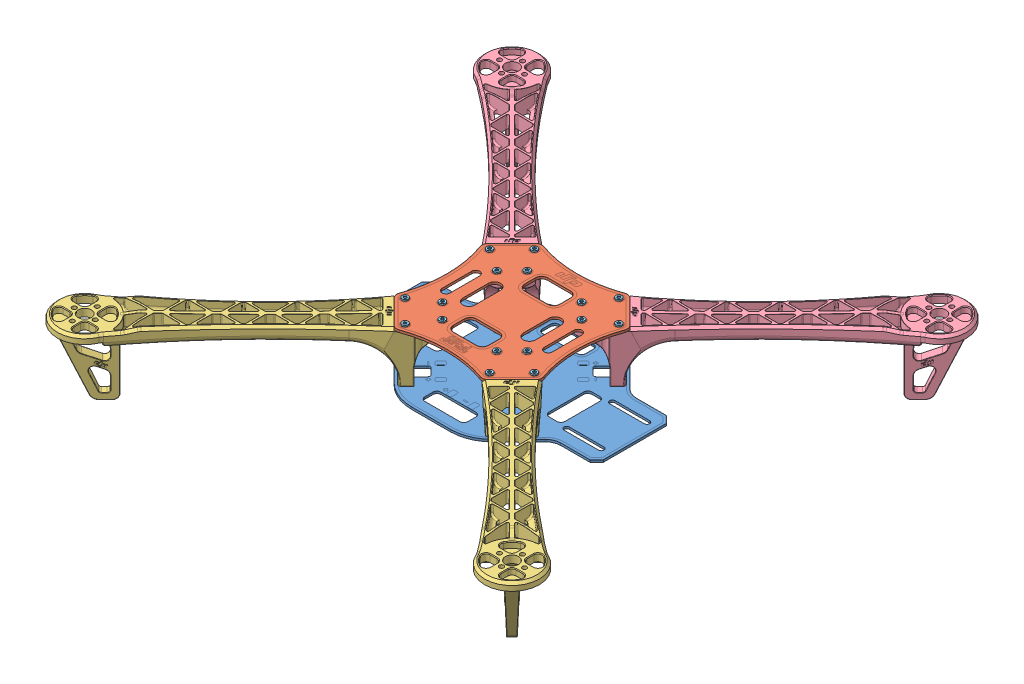
SolidWorks assembly FlameWheel_F450, configuration Default. Lengths in mm.
Overall size (375.45 55.91 375.45).
30 component instances, 5 part files, 134 mates.
Components (placement in the parent):
- FlameWheel_F450_Base_Bottom-1: FlameWheel_F450_Base_Bottom [Default] at (0 -19.2036 0) x (-1 0 0) z (0 0 -1) size (182 1.6 118)
- FlameWheel_F450_Base_Top-1: FlameWheel_F450_Base_Top [Default] at (0 19.2286 0) x (-1 0 0) z (0 0 -1) size (108.15 1.65 108.15)
- FlameWheel_F450_Arm_White-1: FlameWheel_F450_Arm_White [Default] at (98.3674 20.1974 98.378) x (-0.707107 0 0.707107) z (-0.707107 0 -0.707107) size (40.75 55.34 213.92)
- FlameWheel_F450_Arm_White-2: FlameWheel_F450_Arm_White [Default] at (-98.378 20.1974 98.3674) x (-0.707107 0 -0.707107) z (0.707107 0 -0.707107) size (40.75 55.34 213.92)
- FlameWheel_F450_Arm_Red-1: FlameWheel_F450_Arm_Red [Default] at (-98.3674 20.1974 -98.378) x (0.707107 0 -0.707107) z (0.707107 0 0.707107) size (40.75 55.34 213.92)
- FlameWheel_F450_Arm_Red-2: FlameWheel_F450_Arm_Red [Default] at (98.378 20.1974 -98.3674) x (0.707107 0 0.707107) z (-0.707107 0 0.707107) size (40.75 55.34 213.92)
- FlameWheel_F450_Base_Screw-1: FlameWheel_F450_Base_Screw [Default] at (31.5406 20.0546 -20.2253) x (-0.297035 0 0.954867) z (-0.954867 0 -0.297035) size (4.5 7.42 4.5)
- FlameWheel_F450_Base_Screw-2: FlameWheel_F450_Base_Screw [Default] at (20.2269 20.0546 -31.539) x (-0.291663 0 0.956521) z (-0.956521 0 -0.291663) size (4.5 7.42 4.5)
- FlameWheel_F450_Base_Screw-3: FlameWheel_F450_Base_Screw [Default] at (48.0835 20.0546 -31.465) x (-0.305735 0 0.952117) z (-0.952117 0 -0.305735) size (4.5 7.42 4.5)
- FlameWheel_F450_Base_Screw-4: FlameWheel_F450_Base_Screw [Default] at (31.4665 20.0546 -48.082) x (-0.301237 0 0.953549) z (-0.953549 0 -0.301237) size (4.5 7.42 4.5)
- FlameWheel_F450_Base_Screw-5: FlameWheel_F450_Base_Screw [Default] at (48.082 20.0546 31.4665) x (-0.954122 0 -0.299419) z (0.299419 0 -0.954122) size (4.5 7.42 4.5)
- FlameWheel_F450_Base_Screw-6: FlameWheel_F450_Base_Screw [Default] at (31.539 20.0546 20.2269) x (-0.957492 0 -0.28846) z (0.28846 0 -0.957492) size (4.5 7.42 4.5)
- FlameWheel_F450_Base_Screw-7: FlameWheel_F450_Base_Screw [Default] at (20.2253 20.0546 31.5406) x (-0.955334 0 -0.295529) z (0.295529 0 -0.955334) size (4.5 7.42 4.5)
- FlameWheel_F450_Base_Screw-8: FlameWheel_F450_Base_Screw [Default] at (31.465 20.0546 48.0835) x (-0.955194 0 -0.29598) z (0.29598 0 -0.955194) size (4.5 7.42 4.5)
- FlameWheel_F450_Base_Screw-9: FlameWheel_F450_Base_Screw [Default] at (-48.0836 20.0546 31.465) x (0.293117 0 -0.956076) z (0.956076 0 0.293117) size (4.5 7.42 4.5)
- FlameWheel_F450_Base_Screw-10: FlameWheel_F450_Base_Screw [Default] at (-31.4665 20.0546 48.082) x (0.288843 0 -0.957376) z (0.957376 0 0.288843) size (4.5 7.42 4.5)
- FlameWheel_F450_Base_Screw-11: FlameWheel_F450_Base_Screw [Default] at (-20.2269 20.0546 31.539) x (0.306596 0 -0.95184) z (0.95184 0 0.306596) size (4.5 7.42 4.5)
- FlameWheel_F450_Base_Screw-12: FlameWheel_F450_Base_Screw [Default] at (-31.5406 20.0546 20.2253) x (0.301712 0 -0.953399) z (0.953399 0 0.301712) size (4.5 7.42 4.5)
- FlameWheel_F450_Base_Screw-13: FlameWheel_F450_Base_Screw [Default] at (-31.539 20.0546 -20.2269) x (0.953252 0 0.302177) z (-0.302177 0 0.953252) size (4.5 7.42 4.5)
- FlameWheel_F450_Base_Screw-14: FlameWheel_F450_Base_Screw [Default] at (-20.2253 20.0546 -31.5406) x (0.958789 0 0.284118) z (-0.284118 0 0.958789) size (4.5 7.42 4.5)
- FlameWheel_F450_Base_Screw-15: FlameWheel_F450_Base_Screw [Default] at (-31.465 20.0546 -48.0835) x (0.952775 0 0.303679) z (-0.303679 0 0.952775) size (4.5 7.42 4.5)
- FlameWheel_F450_Base_Screw-16: FlameWheel_F450_Base_Screw [Default] at (-48.082 20.0546 -31.4665) x (0.951324 0 0.308194) z (-0.308194 0 0.951324) size (4.5 7.42 4.5)
- FlameWheel_F450_Base_Screw-17: FlameWheel_F450_Base_Screw [Default] at (-32.0325 -20.0046 46.5265) x (-0.841902 0 -0.53963) z (-0.53963 0 0.841902) size (4.5 7.42 4.5)
- FlameWheel_F450_Base_Screw-18: FlameWheel_F450_Base_Screw [Default] at (-46.5282 -20.0046 32.0308) x (-0.845928 0 -0.533297) z (-0.533297 0 0.845928) size (4.5 7.42 4.5)
- FlameWheel_F450_Base_Screw-19: FlameWheel_F450_Base_Screw [Default] at (-46.5265 -20.0046 -32.0325) x (0.545636 0 -0.838023) z (-0.838023 0 -0.545636) size (4.5 7.42 4.5)
- FlameWheel_F450_Base_Screw-20: FlameWheel_F450_Base_Screw [Default] at (32.0325 -20.0046 -46.5265) x (0.846067 0 0.533077) z (0.533077 0 -0.846067) size (4.5 7.42 4.5)
- FlameWheel_F450_Base_Screw-21: FlameWheel_F450_Base_Screw [Default] at (46.5265 -20.0046 32.0325) x (-0.547323 0 0.836921) z (0.836921 0 0.547323) size (4.5 7.42 4.5)
- FlameWheel_F450_Base_Screw-22: FlameWheel_F450_Base_Screw [Default] at (46.5282 -20.0046 -32.0308) x (0.847468 0 0.530847) z (0.530847 0 -0.847468) size (4.5 7.42 4.5)
- FlameWheel_F450_Base_Screw-23: FlameWheel_F450_Base_Screw [Default] at (-32.0308 -20.0046 -46.5282) x (0.54048 0 -0.841357) z (-0.841357 0 -0.54048) size (4.5 7.42 4.5)
- FlameWheel_F450_Base_Screw-24: FlameWheel_F450_Base_Screw [Default] at (32.0308 -20.0046 46.5282) x (-0.540245 0 0.841508) z (0.841508 0 0.540245) size (4.5 7.42 4.5)
Mates (geometry in assembly coordinates):
- Coincident1: coincident aligned: plane of FlameWheel_F450_Base_Bottom-1 through (36.6281 20.0036 51.1238) normal (0.707107 0 0.707107); plane of FlameWheel_F450_Base_Top-1 through (35.0464 -18.4036 52.7056) normal (0.707107 0 0.707107)
- Coincident2: coincident aligned: plane of FlameWheel_F450_Base_Bottom-1 through (-56.4271 20.0036 31.3248) normal (-0.707107 0 0.707107); plane of FlameWheel_F450_Base_Top-1 through (-52.7056 -18.4036 35.0464) normal (-0.707107 0 0.707107)
- Coincident3: coincident aligned: plane of FlameWheel_F450_Base_Bottom-1 through (-32.25 20.0036 -55.502) normal (-0.707107 0 -0.707107); plane of FlameWheel_F450_Base_Top-1 through (-52.7056 -18.4036 -35.0464) normal (-0.707107 0 -0.707107)
- Coincident4: coincident aligned: plane of FlameWheel_F450_Base_Bottom-1 through (32.25 20.0036 -55.502) normal (0.707107 0 -0.707107); plane of FlameWheel_F450_Base_Top-1 through (35.0464 -18.4036 -52.7056) normal (0.707107 0 -0.707107)
- Coincident12: coincident anti-aligned: plane of FlameWheel_F450_Base_Top-1 through (0 -18.4026 0) normal (0 1 0); plane of FlameWheel_F450_Arm_Red-2 through (-31.3302 -18.4026 -53.6641) normal (0 -1 0)
- Coincident13: coincident anti-aligned: plane of FlameWheel_F450_Base_Top-1 through (0 -18.4026 0) normal (0 1 0); plane of FlameWheel_F450_Arm_Red-1 through (53.6641 -18.4026 -31.3302) normal (0 -1 0)
- Coincident14: coincident anti-aligned: plane of FlameWheel_F450_Base_Top-1 through (0 -18.4026 0) normal (0 1 0); plane of FlameWheel_F450_Arm_White-2 through (31.3302 -18.4026 53.6641) normal (0 -1 0)
- Coincident15: coincident anti-aligned: plane of FlameWheel_F450_Base_Top-1 through (0 -18.4026 0) normal (0 1 0); plane of FlameWheel_F450_Arm_White-1 through (-53.6641 -18.4026 31.3302) normal (0 -1 0)
- Concentric10: concentric aligned: circle of FlameWheel_F450_Base_Top-1; circle of FlameWheel_F450_Arm_Red-2
- Concentric11: concentric aligned: circle of FlameWheel_F450_Base_Top-1; circle of FlameWheel_F450_Arm_Red-2
- Concentric12: concentric aligned: circle of FlameWheel_F450_Base_Top-1; circle of FlameWheel_F450_Arm_Red-2
- Concentric13: concentric aligned: circle of FlameWheel_F450_Base_Top-1; circle of FlameWheel_F450_Arm_Red-2
- Concentric14: concentric aligned: circle of FlameWheel_F450_Base_Top-1; circle of FlameWheel_F450_Arm_Red-1
- Concentric15: concentric aligned: circle of FlameWheel_F450_Base_Top-1; circle of FlameWheel_F450_Arm_Red-1
- Concentric16: concentric aligned: circle of FlameWheel_F450_Base_Top-1; circle of FlameWheel_F450_Arm_Red-1
- Concentric17: concentric aligned: circle of FlameWheel_F450_Base_Top-1; circle of FlameWheel_F450_Arm_Red-1
- Concentric18: concentric aligned: circle of FlameWheel_F450_Base_Top-1; circle of FlameWheel_F450_Arm_White-2
- Concentric19: concentric aligned: circle of FlameWheel_F450_Base_Top-1; circle of FlameWheel_F450_Arm_White-2
- Concentric20: concentric aligned: circle of FlameWheel_F450_Base_Top-1; circle of FlameWheel_F450_Arm_White-2
- Concentric21: concentric aligned: circle of FlameWheel_F450_Base_Top-1; circle of FlameWheel_F450_Arm_White-2
- Concentric22: concentric aligned: circle of FlameWheel_F450_Base_Top-1; circle of FlameWheel_F450_Arm_White-1
- Concentric23: concentric aligned: circle of FlameWheel_F450_Base_Top-1; circle of FlameWheel_F450_Arm_White-1
- Concentric24: concentric aligned: circle of FlameWheel_F450_Base_Top-1; circle of FlameWheel_F450_Arm_White-1
- Concentric25: concentric aligned: circle of FlameWheel_F450_Base_Top-1; circle of FlameWheel_F450_Arm_White-1
- Concentric26: concentric anti-aligned: circle of FlameWheel_F450_Base_Bottom-1; circle of FlameWheel_F450_Arm_White-2
- Concentric27: concentric anti-aligned: circle of FlameWheel_F450_Base_Bottom-1; circle of FlameWheel_F450_Arm_White-2
- Concentric28: concentric anti-aligned: circle of FlameWheel_F450_Base_Bottom-1; circle of FlameWheel_F450_Arm_Red-1
- Concentric29: concentric anti-aligned: circle of FlameWheel_F450_Base_Bottom-1; circle of FlameWheel_F450_Arm_Red-1
- Concentric30: concentric anti-aligned: circle of FlameWheel_F450_Base_Bottom-1; circle of FlameWheel_F450_Arm_Red-2
- Concentric31: concentric anti-aligned: circle of FlameWheel_F450_Base_Bottom-1; circle of FlameWheel_F450_Arm_Red-2
- Concentric32: concentric anti-aligned: circle of FlameWheel_F450_Base_Bottom-1; circle of FlameWheel_F450_Arm_White-1
- Concentric33: concentric anti-aligned: circle of FlameWheel_F450_Base_Bottom-1; circle of FlameWheel_F450_Arm_White-1
- Coincident24: coincident anti-aligned: plane of FlameWheel_F450_Base_Bottom-1 through (0 18.4026 0) normal (0 -1 0); plane of FlameWheel_F450_Arm_White-1 through (-36.8349 18.4026 47.3108) normal (0 1 0)
- Coincident25: coincident anti-aligned: plane of FlameWheel_F450_Base_Bottom-1 through (0 18.4026 0) normal (0 -1 0); plane of FlameWheel_F450_Arm_White-1 through (-51.0813 18.4026 31.9315) normal (0 1 0)
- Coincident26: coincident anti-aligned: plane of FlameWheel_F450_Base_Bottom-1 through (0 18.4026 0) normal (0 -1 0); plane of FlameWheel_F450_Arm_White-2 through (31.9315 18.4026 51.0813) normal (0 1 0)
- Coincident27: coincident anti-aligned: plane of FlameWheel_F450_Base_Bottom-1 through (0 18.4026 0) normal (0 -1 0); plane of FlameWheel_F450_Arm_White-2 through (47.3108 18.4026 36.8349) normal (0 1 0)
- Coincident28: coincident anti-aligned: plane of FlameWheel_F450_Base_Bottom-1 through (0 18.4026 0) normal (0 -1 0); plane of FlameWheel_F450_Arm_Red-1 through (51.0813 18.4026 -31.9315) normal (0 1 0)
- Coincident29: coincident anti-aligned: plane of FlameWheel_F450_Base_Bottom-1 through (0 18.4026 0) normal (0 -1 0); plane of FlameWheel_F450_Arm_Red-1 through (36.8349 18.4026 -47.3108) normal (0 1 0)
- Coincident30: coincident anti-aligned: plane of FlameWheel_F450_Base_Bottom-1 through (0 18.4026 0) normal (0 -1 0); plane of FlameWheel_F450_Arm_Red-2 through (-31.9315 18.4026 -51.0813) normal (0 1 0)
- Coincident31: coincident anti-aligned: plane of FlameWheel_F450_Base_Bottom-1 through (0 18.4026 0) normal (0 -1 0); plane of FlameWheel_F450_Arm_Red-2 through (-47.3108 18.4026 -36.8349) normal (0 1 0)
- Coincident32: coincident: point of FlameWheel_F450_Arm_White-1; point of FlameWheel_F450_Arm_White-2
- Coincident33: coincident: point of FlameWheel_F450_Arm_White-1; point of FlameWheel_F450_Arm_Red-2
- Coincident34: coincident: point of FlameWheel_F450_Arm_White-2; point of FlameWheel_F450_Arm_Red-2
- Coincident35: coincident: point of FlameWheel_F450_Arm_Red-1; point of FlameWheel_F450_Arm_Red-2
- Coincident36: coincident: point of FlameWheel_F450_Arm_White-1; point of FlameWheel_F450_Arm_Red-1
- Coincident37: coincident: point of FlameWheel_F450_Arm_White-2; point of FlameWheel_F450_Arm_Red-1
- Coincident38: coincident: unknown of ?
- Coincident39: coincident: unknown of ?
- Coincident40: coincident: unknown of ?
- Coincident41: coincident: unknown of ?
- Coincident44: coincident anti-aligned: plane of FlameWheel_F450_Base_Bottom-1 through (0 20.0046 0) normal (0 1 0); plane of FlameWheel_F450_Base_Screw-24 through (-32.0308 20.0046 46.5282) normal (0 -1 0)
- Coincident45: coincident anti-aligned: plane of FlameWheel_F450_Base_Bottom-1 through (0 20.0046 0) normal (0 1 0); plane of FlameWheel_F450_Base_Screw-17 through (32.0325 20.0046 46.5265) normal (0 -1 0)
- Coincident46: coincident anti-aligned: plane of FlameWheel_F450_Base_Bottom-1 through (0 20.0046 0) normal (0 1 0); plane of FlameWheel_F450_Base_Screw-19 through (46.5265 20.0046 -32.0325) normal (0 -1 0)
- Coincident47: coincident anti-aligned: plane of FlameWheel_F450_Base_Bottom-1 through (0 20.0046 0) normal (0 1 0); plane of FlameWheel_F450_Base_Screw-23 through (32.0308 20.0046 -46.5282) normal (0 -1 0)
- Coincident48: coincident anti-aligned: plane of FlameWheel_F450_Base_Bottom-1 through (0 20.0046 0) normal (0 1 0); plane of FlameWheel_F450_Base_Screw-18 through (46.5282 20.0046 32.0308) normal (0 -1 0)
- Coincident49: coincident anti-aligned: plane of FlameWheel_F450_Base_Bottom-1 through (0 20.0046 0) normal (0 1 0); plane of FlameWheel_F450_Base_Screw-20 through (-32.0325 20.0046 -46.5265) normal (0 -1 0)
- Coincident50: coincident anti-aligned: plane of FlameWheel_F450_Base_Bottom-1 through (0 20.0046 0) normal (0 1 0); plane of FlameWheel_F450_Base_Screw-22 through (-46.5282 20.0046 -32.0308) normal (0 -1 0)
- Coincident51: coincident anti-aligned: plane of FlameWheel_F450_Base_Bottom-1 through (0 20.0046 0) normal (0 1 0); plane of FlameWheel_F450_Base_Screw-21 through (-46.5265 20.0046 32.0325) normal (0 -1 0)
- Coincident53: coincident anti-aligned: plane of FlameWheel_F450_Base_Top-1 through (0 -20.0546 0) normal (0 -1 0); plane of FlameWheel_F450_Base_Screw-5 through (-48.082 -20.0546 31.4665) normal (0 1 0)
- Coincident54: coincident anti-aligned: plane of FlameWheel_F450_Base_Top-1 through (0 -20.0546 0) normal (0 -1 0); plane of FlameWheel_F450_Base_Screw-8 through (-31.465 -20.0546 48.0835) normal (0 1 0)
- Coincident55: coincident anti-aligned: plane of FlameWheel_F450_Base_Top-1 through (0 -20.0546 0) normal (0 -1 0); plane of FlameWheel_F450_Base_Screw-6 through (-31.539 -20.0546 20.2269) normal (0 1 0)
- Coincident56: coincident anti-aligned: plane of FlameWheel_F450_Base_Top-1 through (0 -20.0546 0) normal (0 -1 0); plane of FlameWheel_F450_Base_Screw-7 through (-20.2253 -20.0546 31.5406) normal (0 1 0)
- Coincident57: coincident anti-aligned: plane of FlameWheel_F450_Base_Top-1 through (0 -20.0546 0) normal (0 -1 0); plane of FlameWheel_F450_Base_Screw-1 through (-31.5406 -20.0546 -20.2253) normal (0 1 0)
- Coincident59: coincident anti-aligned: plane of FlameWheel_F450_Base_Top-1 through (0 -20.0546 0) normal (0 -1 0); plane of FlameWheel_F450_Base_Screw-3 through (-48.0835 -20.0546 -31.465) normal (0 1 0)
- Coincident60: coincident anti-aligned: plane of FlameWheel_F450_Base_Top-1 through (0 -20.0546 0) normal (0 -1 0); plane of FlameWheel_F450_Base_Screw-4 through (-31.4665 -20.0546 -48.082) normal (0 1 0)
- Coincident61: coincident anti-aligned: plane of FlameWheel_F450_Base_Top-1 through (0 -20.0546 0) normal (0 -1 0); plane of FlameWheel_F450_Base_Screw-2 through (-20.2269 -20.0546 -31.539) normal (0 1 0)
- Coincident62: coincident anti-aligned: plane of FlameWheel_F450_Base_Top-1 through (0 -20.0546 0) normal (0 -1 0); plane of FlameWheel_F450_Base_Screw-10 through (31.4665 -20.0546 48.082) normal (0 1 0)
- Coincident63: coincident anti-aligned: plane of FlameWheel_F450_Base_Top-1 through (0 -20.0546 0) normal (0 -1 0); plane of FlameWheel_F450_Base_Screw-9 through (48.0836 -20.0546 31.465) normal (0 1 0)
- Coincident64: coincident anti-aligned: plane of FlameWheel_F450_Base_Top-1 through (0 -20.0546 0) normal (0 -1 0); plane of FlameWheel_F450_Base_Screw-13 through (31.539 -20.0546 -20.2269) normal (0 1 0)
- Coincident65: coincident anti-aligned: plane of FlameWheel_F450_Base_Top-1 through (0 -20.0546 0) normal (0 -1 0); plane of FlameWheel_F450_Base_Screw-14 through (20.2253 -20.0546 -31.5406) normal (0 1 0)
- Coincident66: coincident anti-aligned: plane of FlameWheel_F450_Base_Top-1 through (0 -20.0546 0) normal (0 -1 0); plane of FlameWheel_F450_Base_Screw-11 through (20.2269 -20.0546 31.539) normal (0 1 0)
- Coincident67: coincident anti-aligned: plane of FlameWheel_F450_Base_Top-1 through (0 -20.0546 0) normal (0 -1 0); plane of FlameWheel_F450_Base_Screw-12 through (31.5406 -20.0546 20.2253) normal (0 1 0)
- Coincident70: coincident anti-aligned: plane of FlameWheel_F450_Base_Top-1 through (0 -20.0546 0) normal (0 -1 0); plane of FlameWheel_F450_Base_Screw-15 through (31.465 -20.0546 -48.0835) normal (0 1 0)
- Coincident71: coincident anti-aligned: plane of FlameWheel_F450_Base_Top-1 through (0 -20.0546 0) normal (0 -1 0); plane of FlameWheel_F450_Base_Screw-16 through (48.082 -20.0546 -31.4665) normal (0 1 0)
- Coincident72: coincident aligned: line of FlameWheel_F450_Base_Top-1 through (-48.0833 -20.0546 31.4663) axis (0 1 0); line of FlameWheel_F450_Base_Screw-5 through (-48.0833 -20.0546 31.4663) axis (0 1 0)
- Coincident73: coincident aligned: line of FlameWheel_F450_Base_Top-1 through (-31.4663 -20.0546 48.0833) axis (0 1 0); line of FlameWheel_F450_Base_Screw-8 through (-31.4663 -20.0546 48.0833) axis (0 1 0)
- Coincident74: coincident anti-aligned: line of FlameWheel_F450_Base_Top-1 through (-31.5403 -18.4026 20.2266) axis (0 -1 0); line of FlameWheel_F450_Base_Screw-6 through (-31.5403 -20.0546 20.2266) axis (0 1 0)
- Coincident75: coincident aligned: line of FlameWheel_F450_Base_Top-1 through (-20.2266 -20.0546 31.5403) axis (0 1 0); line of FlameWheel_F450_Base_Screw-7 through (-20.2266 -20.0546 31.5403) axis (0 1 0)
- Coincident76: coincident aligned: line of FlameWheel_F450_Base_Top-1 through (-48.0833 -20.0546 -31.4663) axis (0 1 0); line of FlameWheel_F450_Base_Screw-3 through (-48.0833 -20.0546 -31.4663) axis (0 1 0)
- Coincident77: coincident aligned: line of FlameWheel_F450_Base_Top-1 through (-31.5403 -20.0546 -20.2266) axis (0 1 0); line of FlameWheel_F450_Base_Screw-1 through (-31.5403 -20.0546 -20.2266) axis (0 1 0)
- Coincident78: coincident aligned: line of FlameWheel_F450_Base_Top-1 through (-31.4663 -20.0546 -48.0833) axis (0 1 0); line of FlameWheel_F450_Base_Screw-4 through (-31.4663 -20.0546 -48.0833) axis (0 1 0)
- Coincident79: coincident aligned: line of FlameWheel_F450_Base_Top-1 through (-20.2266 -20.0546 -31.5403) axis (0 1 0); line of FlameWheel_F450_Base_Screw-2 through (-20.2266 -20.0546 -31.5403) axis (0 1 0)
- Coincident80: coincident aligned: line of FlameWheel_F450_Base_Top-1 through (31.4663 -20.0546 48.0833) axis (0 1 0); line of FlameWheel_F450_Base_Screw-10 through (31.4663 -20.0546 48.0833) axis (0 1 0)
- Coincident81: coincident aligned: line of FlameWheel_F450_Base_Top-1 through (48.0833 -20.0546 31.4663) axis (0 1 0); line of FlameWheel_F450_Base_Screw-9 through (48.0833 -20.0546 31.4663) axis (0 1 0)
- Coincident82: coincident aligned: line of FlameWheel_F450_Base_Top-1 through (20.2266 -20.0546 31.5403) axis (0 1 0); line of FlameWheel_F450_Base_Screw-11 through (20.2266 -20.0546 31.5403) axis (0 1 0)
- Coincident83: coincident aligned: line of FlameWheel_F450_Base_Top-1 through (31.5403 -20.0546 20.2266) axis (0 1 0); line of FlameWheel_F450_Base_Screw-12 through (31.5403 -20.0546 20.2266) axis (0 1 0)
- Coincident84: coincident aligned: line of FlameWheel_F450_Base_Top-1 through (31.5403 -20.0546 -20.2266) axis (0 1 0); line of FlameWheel_F450_Base_Screw-13 through (31.5403 -20.0546 -20.2266) axis (0 1 0)
- Coincident85: coincident aligned: line of FlameWheel_F450_Base_Top-1 through (20.2266 -20.0546 -31.5403) axis (0 1 0); line of FlameWheel_F450_Base_Screw-14 through (20.2266 -20.0546 -31.5403) axis (0 1 0)
- Coincident86: coincident aligned: line of FlameWheel_F450_Base_Top-1 through (31.4663 -20.0546 -48.0833) axis (0 1 0); line of FlameWheel_F450_Base_Screw-15 through (31.4663 -20.0546 -48.0833) axis (0 1 0)
- Coincident87: coincident aligned: line of FlameWheel_F450_Base_Top-1 through (48.0833 -20.0546 -31.4663) axis (0 1 0); line of FlameWheel_F450_Base_Screw-16 through (48.0833 -20.0546 -31.4663) axis (0 1 0)
- Coincident88: coincident anti-aligned: line of FlameWheel_F450_Base_Bottom-1 through (-32.0319 18.4026 46.5276) axis (0 1 0); line of FlameWheel_F450_Base_Screw-24 through (-32.0319 20.0046 46.5276) axis (0 -1 0)
- Coincident89: coincident anti-aligned: line of FlameWheel_F450_Base_Bottom-1 through (-46.5276 18.4026 32.0319) axis (0 1 0); line of FlameWheel_F450_Base_Screw-21 through (-46.5276 20.0046 32.0319) axis (0 -1 0)
- Coincident90: coincident anti-aligned: line of FlameWheel_F450_Base_Bottom-1 through (-46.5276 18.4026 -32.0319) axis (0 1 0); line of FlameWheel_F450_Base_Screw-22 through (-46.5276 20.0046 -32.0319) axis (0 -1 0)
- Coincident91: coincident anti-aligned: line of FlameWheel_F450_Base_Bottom-1 through (-32.0319 18.4026 -46.5276) axis (0 1 0); line of FlameWheel_F450_Base_Screw-20 through (-32.0319 20.0046 -46.5276) axis (0 -1 0)
- Coincident92: coincident anti-aligned: line of FlameWheel_F450_Base_Bottom-1 through (32.0319 18.4026 -46.5276) axis (0 1 0); line of FlameWheel_F450_Base_Screw-23 through (32.0319 20.0046 -46.5276) axis (0 -1 0)
- Coincident93: coincident anti-aligned: line of FlameWheel_F450_Base_Bottom-1 through (46.5276 18.4026 -32.0319) axis (0 1 0); line of FlameWheel_F450_Base_Screw-19 through (46.5276 20.0046 -32.0319) axis (0 -1 0)
- Coincident94: coincident anti-aligned: line of FlameWheel_F450_Base_Bottom-1 through (46.5276 18.4026 32.0319) axis (0 1 0); line of FlameWheel_F450_Base_Screw-18 through (46.5276 20.0046 32.0319) axis (0 -1 0)
- Coincident95: coincident aligned: line of FlameWheel_F450_Base_Bottom-1 through (32.0319 20.0046 46.5276) axis (0 -1 0); line of FlameWheel_F450_Base_Screw-17 through (32.0319 20.0046 46.5276) axis (0 -1 0)
- Screw1: screw = 0.45 mm aligned: line of FlameWheel_F450_Base_Bottom-1 through (-32.0319 -20.0046 46.5276) axis (0 1 0); line of FlameWheel_F450_Base_Screw-17 through (32.0319 20.0046 46.5276) axis (0 -1 0)
- Screw2: screw = 0.45 mm anti-aligned: line of FlameWheel_F450_Base_Bottom-1 through (-46.5276 -18.4026 32.0319) axis (0 -1 0); line of FlameWheel_F450_Base_Screw-18 through (46.5276 20.0046 32.0319) axis (0 -1 0)
- Screw3: screw = 0.45 mm anti-aligned: line of FlameWheel_F450_Base_Bottom-1 through (-46.5276 -18.4026 -32.0319) axis (0 -1 0); line of FlameWheel_F450_Base_Screw-19 through (46.5276 20.0046 -32.0319) axis (0 -1 0)
- Screw4: screw = 0.45 mm anti-aligned: line of FlameWheel_F450_Base_Bottom-1 through (-32.0319 -18.4026 -46.5276) axis (0 -1 0); line of FlameWheel_F450_Base_Screw-23 through (32.0319 20.0046 -46.5276) axis (0 -1 0)
- Screw5: screw = 0.45 mm anti-aligned: line of FlameWheel_F450_Base_Bottom-1 through (32.0319 -18.4026 -46.5276) axis (0 -1 0); line of FlameWheel_F450_Base_Screw-20 through (-32.0319 20.0046 -46.5276) axis (0 -1 0)
- Screw6: screw = 0.45 mm anti-aligned: line of FlameWheel_F450_Base_Bottom-1 through (46.5276 -18.4026 -32.0319) axis (0 -1 0); line of FlameWheel_F450_Base_Screw-22 through (-46.5276 20.0046 -32.0319) axis (0 -1 0)
- Screw7: screw = 0.45 mm anti-aligned: line of FlameWheel_F450_Base_Bottom-1 through (46.5276 -18.4026 32.0319) axis (0 -1 0); line of FlameWheel_F450_Base_Screw-21 through (-46.5276 20.0046 32.0319) axis (0 -1 0)
- Screw8: screw = 0.45 mm anti-aligned: line of FlameWheel_F450_Base_Bottom-1 through (32.0319 -18.4026 46.5276) axis (0 -1 0); line of FlameWheel_F450_Base_Screw-24 through (-32.0319 20.0046 46.5276) axis (0 -1 0)
- Lock1: lock: unknown of FlameWheel_F450_Base_Top-1; unknown of FlameWheel_F450_Base_Screw-14
- Lock2: lock: unknown of FlameWheel_F450_Base_Top-1; unknown of FlameWheel_F450_Base_Screw-13
- Lock3: lock: unknown of FlameWheel_F450_Base_Top-1; unknown of FlameWheel_F450_Base_Screw-15
- Lock4: lock: unknown of FlameWheel_F450_Base_Top-1; unknown of FlameWheel_F450_Base_Screw-16
- Lock5: lock: unknown of FlameWheel_F450_Base_Top-1; unknown of FlameWheel_F450_Base_Screw-12
- Lock6: lock: unknown of FlameWheel_F450_Base_Top-1; unknown of FlameWheel_F450_Base_Screw-9
- Lock7: lock: unknown of FlameWheel_F450_Base_Top-1; unknown of FlameWheel_F450_Base_Screw-11
- Lock8: lock: unknown of FlameWheel_F450_Base_Top-1; unknown of FlameWheel_F450_Base_Screw-10
- Lock9: lock: unknown of FlameWheel_F450_Base_Top-1; unknown of FlameWheel_F450_Base_Screw-8
- Lock10: lock: unknown of FlameWheel_F450_Base_Top-1; unknown of FlameWheel_F450_Base_Screw-7
- Lock11: lock: unknown of FlameWheel_F450_Base_Top-1; unknown of FlameWheel_F450_Base_Screw-6
- Lock12: lock: unknown of FlameWheel_F450_Base_Top-1; unknown of FlameWheel_F450_Base_Screw-5
- Lock13: lock: unknown of FlameWheel_F450_Base_Top-1; unknown of FlameWheel_F450_Base_Screw-1
- Lock14: lock: unknown of FlameWheel_F450_Base_Top-1; unknown of FlameWheel_F450_Base_Screw-2
- Lock15: lock: unknown of FlameWheel_F450_Base_Top-1; unknown of FlameWheel_F450_Base_Screw-3
- Lock16: lock: unknown of FlameWheel_F450_Base_Top-1; unknown of FlameWheel_F450_Base_Screw-4
- Lock19: lock: unknown of FlameWheel_F450_Base_Bottom-1; unknown of FlameWheel_F450_Base_Screw-20
- Lock20: lock: unknown of FlameWheel_F450_Base_Bottom-1; unknown of FlameWheel_F450_Base_Screw-22
- Lock21: lock: unknown of FlameWheel_F450_Base_Bottom-1; unknown of FlameWheel_F450_Base_Screw-21
- Lock22: lock: unknown of FlameWheel_F450_Base_Bottom-1; unknown of FlameWheel_F450_Base_Screw-24
- Lock23: lock: unknown of FlameWheel_F450_Base_Bottom-1; unknown of FlameWheel_F450_Base_Screw-17
- Lock24: lock: unknown of FlameWheel_F450_Base_Bottom-1; unknown of FlameWheel_F450_Base_Screw-18
- Lock25: lock: unknown of FlameWheel_F450_Base_Bottom-1; unknown of FlameWheel_F450_Base_Screw-19
- Lock26: lock: unknown of FlameWheel_F450_Base_Bottom-1; unknown of FlameWheel_F450_Base_Screw-23
- Parallel35: parallel aligned: plane of FlameWheel_F450_Base_Bottom-1 through (-14.43 20.0036 60.3186) normal (0 0 1); plane of assembly through (0 0 0) normal (0 0 1)
- Parallel36: parallel anti-aligned: plane of FlameWheel_F450_Base_Bottom-1 through (-27.75 20.0036 -57.6814) normal (0 0 -1); plane of assembly through (0 0 0) normal (0 0 1)
- Parallel37: parallel anti-aligned: plane of FlameWheel_F450_Base_Bottom-1 through (-91 -20.0036 -23.9371) normal (-1 0 0); plane of assembly through (0 0 0) normal (1 0 0)
- Parallel38: parallel aligned: plane of FlameWheel_F450_Base_Bottom-1 through (-91 20.0036 -23.9371) normal (-1 0 0); plane of assembly through (0 0 0) normal (1 0 0)
